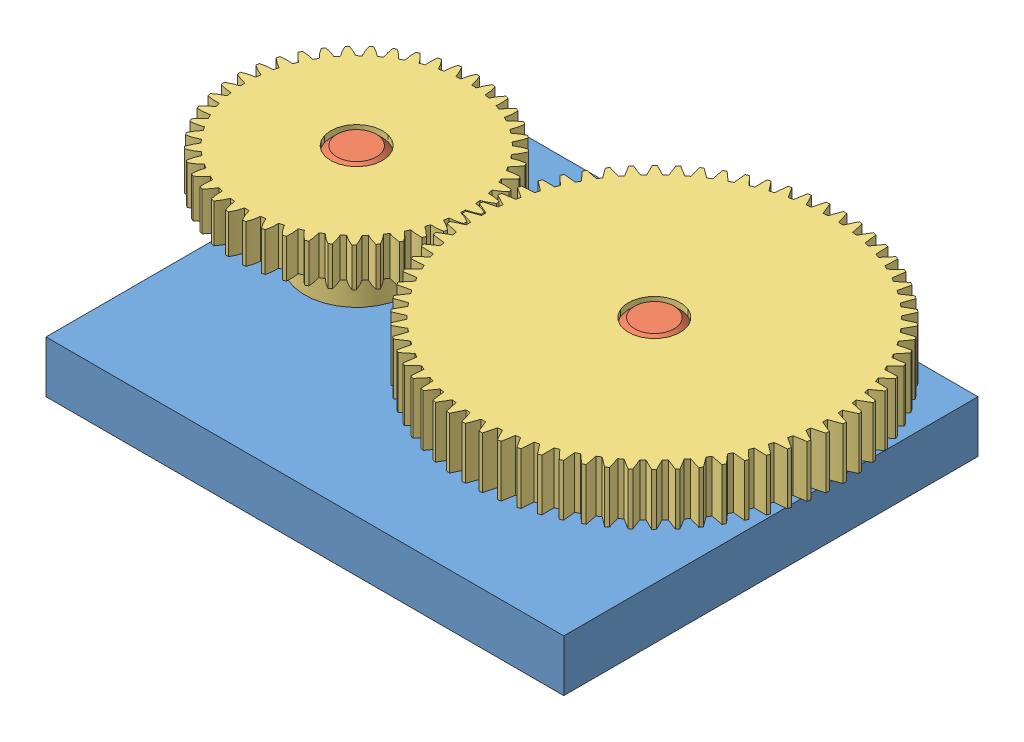
SolidWorks assembly Question 3c - Assembly, configuration Default. Lengths in mm.
Overall size (168.56 40.64 118.95).
5 component instances, 3 part files, 9 mates.
Components (placement in the parent):
- Question 3a-1: Question 3a [Default] at (-123.5053 0.4791 -23.7757) size (127 12.7 101.6)
- Question 3b-1: Question 3b [Default] at (-25.0803 0.4791 27.0243) size (12.7 40.64 12.7)
- Question 3b-2: Question 3b [Default] at (-98.1053 0.4791 27.0243) size (12.7 40.64 12.7)
- spur gear_ai-3: spur gear_ai [Inch - Spur gear 20DP 45T 20PA 0.375FW ---S45O1H1L0.5N] at (-98.1053 31.5942 27.0243) x (0 1 0) z (-0.239625 0 0.970865) size (25.4 59.64 59.68)
- spur gear_ai-4: spur gear_ai [Inch - Spur gear 20DP 70T 20PA 0.5FW ---S70O1H1L0.5N] at (-25.0803 28.4192 27.0243) x (0 1 0) z (-0.373515 0 0.927624) size (25.4 91.38 91.44)
Mates (geometry in assembly coordinates):
- Concentric1: concentric aligned: cylinder of Question 3a-1 through (-98.1053 13.1791 27.0243) axis (0 -1 0) radius 6.35; cylinder of Question 3b-2 through (-98.1053 41.1191 27.0243) axis (0 -1 0) radius 6.35
- Coincident1: coincident aligned: plane of Question 3a-1 through (-123.5053 0.4791 -23.7757) normal (0 -1 0); plane of Question 3b-2 through (-98.1053 0.4791 27.0243) normal (0 -1 0)
- Concentric2: concentric aligned: cylinder of Question 3a-1 through (-25.0803 13.1791 27.0243) axis (0 -1 0) radius 6.35; cylinder of Question 3b-1 through (-25.0803 41.1191 27.0243) axis (0 -1 0) radius 6.35
- Coincident2: coincident aligned: plane of Question 3a-1 through (-123.5053 0.4791 -23.7757) normal (0 -1 0); plane of Question 3b-1 through (-25.0803 0.4791 27.0243) normal (0 -1 0)
- Concentric3: concentric aligned: cylinder of Question 3b-2 through (-98.1053 41.1191 27.0243) axis (0 -1 0) radius 6.35; cylinder of spur gear_ai-3 through (-98.1053 56.9943 27.0243) axis (0 -1 0) radius 6.35
- Distance1: distance = 2.54 mm anti-aligned: plane of spur gear_ai-3 through (-98.1053 15.7191 27.0243) normal (0 -1 0); plane of Question 3a-1 through (-123.5053 13.1791 -23.7757) normal (0 1 0)
- Concentric4: concentric aligned: cylinder of Question 3b-1 through (-25.0803 41.1191 27.0243) axis (0 -1 0) radius 6.35; cylinder of spur gear_ai-4 through (-25.0803 53.8193 27.0243) axis (0 -1 0) radius 6.35
- Distance2: distance = 2.54 mm anti-aligned: plane of spur gear_ai-4 through (-25.0803 15.7191 27.0243) normal (0 -1 0); plane of Question 3a-1 through (-123.5053 13.1791 -23.7757) normal (0 1 0)
- GearMate1: gear = 1778 : 1143 mm: cylinder of spur gear_ai-3 through (-98.1053 56.9943 27.0243) axis (0 -1 0) radius 6.35; cylinder of spur gear_ai-4 through (-25.0803 53.8193 27.0243) axis (0 -1 0) radius 6.35
